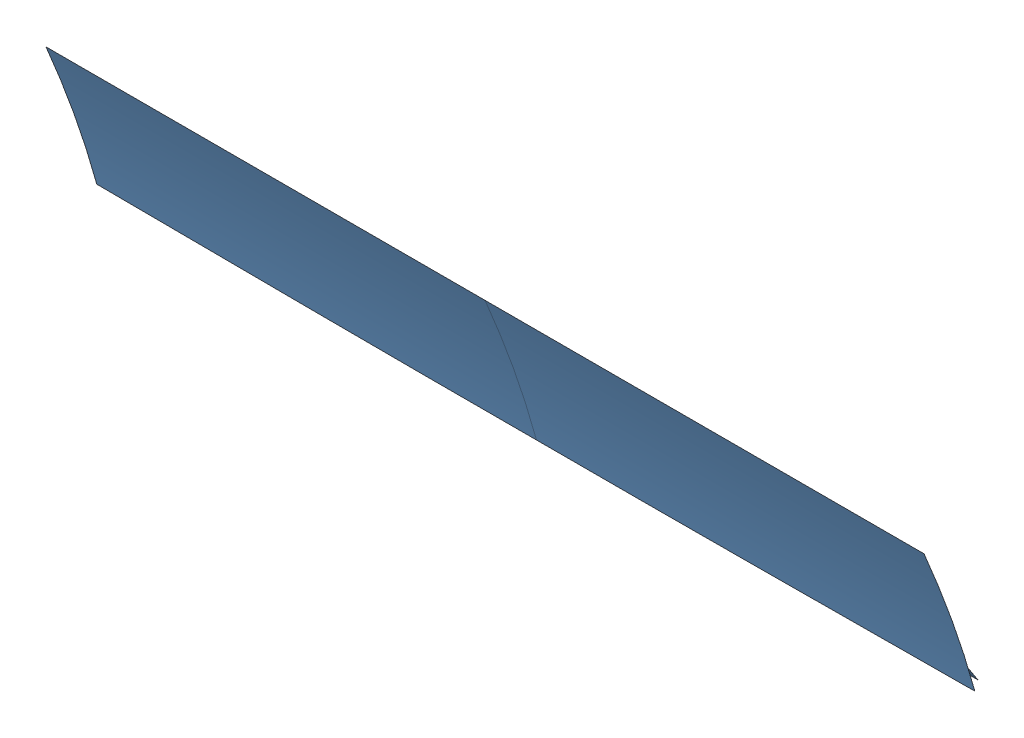
SolidWorks assembly gear_conection_V2, configuration Default. Lengths in mm.
Overall size (15.11 158.69 121.74).
2 component instances, 1 part files, 10 mates.
Components (placement in the parent):
- epifanies_katatomon-3: epifanies_katatomon [gear1] at (0 -56.25 0) x (0 -0.08486 -0.996393) z (1 0 0) size (112.5 113.7 15)
- epifanies_katatomon-4: epifanies_katatomon [gear2] at (0 -53.827 -18.9096) x (0 0.252128 -0.967694) z (1 0 0) size (37.5 38.72 14.23)
Mates (geometry in assembly coordinates):
- GearMate1: gear = 56.25 : 18.75 mm: line of epifanies_katatomon-4 through (1.5 18.75 0) axis (-1 0 0); line of epifanies_katatomon-3 through (1.5 -56.2579 0) axis (-0.999986 0.005236 0)
- Coincident8: coincident: line of assembly; line of assembly; line of epifanies_katatomon-4 through (1.5 18.75 0) axis (-1 0 0)
- Coincident9: coincident aligned: line of epifanies_katatomon-3 through (1.5 -56.25 0) axis (-1 0 0)
- Coincident10: coincident: point of epifanies_katatomon-3; point of assembly
- Coincident11: coincident: point of epifanies_katatomon-4; point of assembly
- Tangent3: tangent: curve of epifanies_katatomon-3
- Tangent5: tangent: edge_curve of epifanies_katatomon-3; edge_curve of ?
- Tangent6: tangent: edge_curve of ?; edge_curve of ?
- Tangent9: tangent: edge_curve of epifanies_katatomon-3; edge_curve of ?
- Tangent10: tangent: curve of epifanies_katatomon-3; curve of epifanies_katatomon-4
